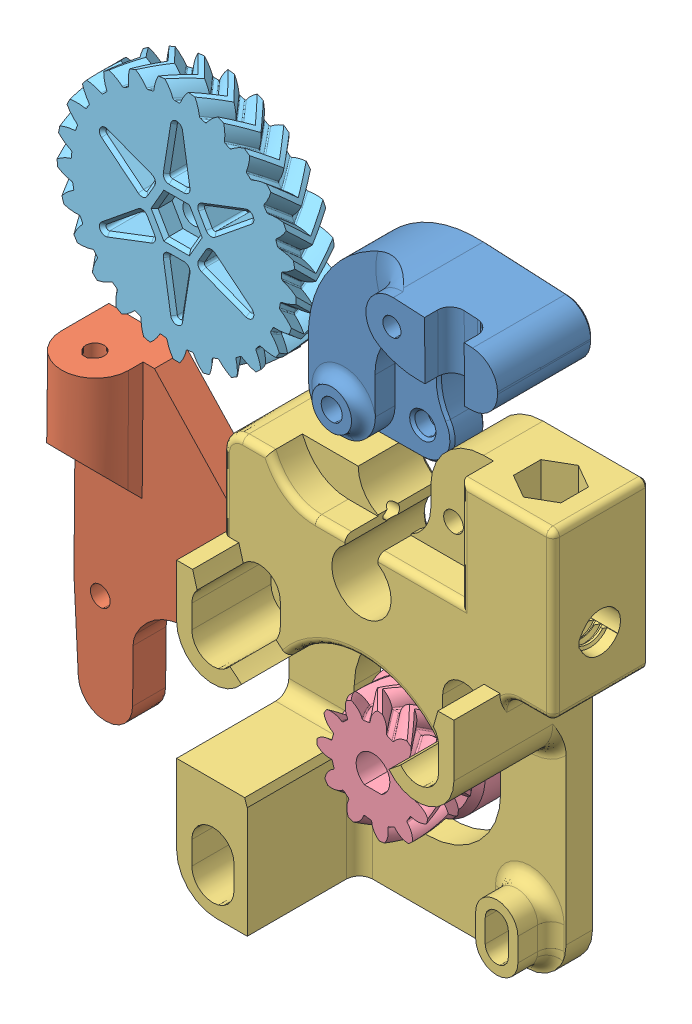
SolidWorks assembly build-plate, configuration Default. Lengths in mm.
Overall size (83.68 90.91 24.5).
5 component instances, 5 part files, 5 mates.
Components (placement in the parent):
- 1309-1: 1309 [Default] at (41.2162 59.5107 8) x (-0.009122 0.999958 0) z (0 0 -1) size (28.5 35.3 14.5)
- 1308-1: 1308 [printed] at (21.4786 26.5771 0) x (-0.999962 0.008727 0) z (0 0 1) size (28.5 50 12.3)
- 1306-1: 1306 [Default] at (50.4178 18.7327 0) size (50 69 21.5)
- 1310-1: 1310 [ISO - RH Helical gear 1M 17T 45HA 20PA 12FW ---17A75H50L0.8N] at (50.6663 18.1926 9.5) x (0 0 -1) z (1 0 0) size (13 18 18)
- 1311-1: 1311 [ISO - RH Helical gear 1M 17T 45HA 20PA 12FW ---17A75H50L0.8N] at (13.9181 68.4606 6) x (0 0 -1) z (1 0 0) size (9 36.33 36.3)
Mates (geometry in assembly coordinates):
- Coincident1: coincident anti-aligned: plane of 1306-1 through (50.4178 53.813 0) normal (0 0 -1); plane of assembly through (0 0 0) normal (0 0 1)
- Coincident2: coincident aligned: plane of 1309-1 through (40.4162 59.5034 0) normal (0 0 -1); plane of 1306-1 through (50.4178 53.813 0) normal (0 0 -1)
- Coincident3: coincident aligned: plane of 1306-1 through (50.4178 53.813 0) normal (0 0 -1); plane of 1311-1 through (13.9181 68.4606 0) normal (0 0 -1)
- Coincident4: coincident aligned: plane of 1306-1 through (50.4178 53.813 0) normal (0 0 -1); plane of 1310-1 through (50.6663 18.1926 0) normal (0 0 -1)
- Coincident5: coincident aligned: plane of 1308-1 through (10.3219 8.6737 0) normal (0 0 -1); plane of 1306-1 through (50.4178 53.813 0) normal (0 0 -1)
